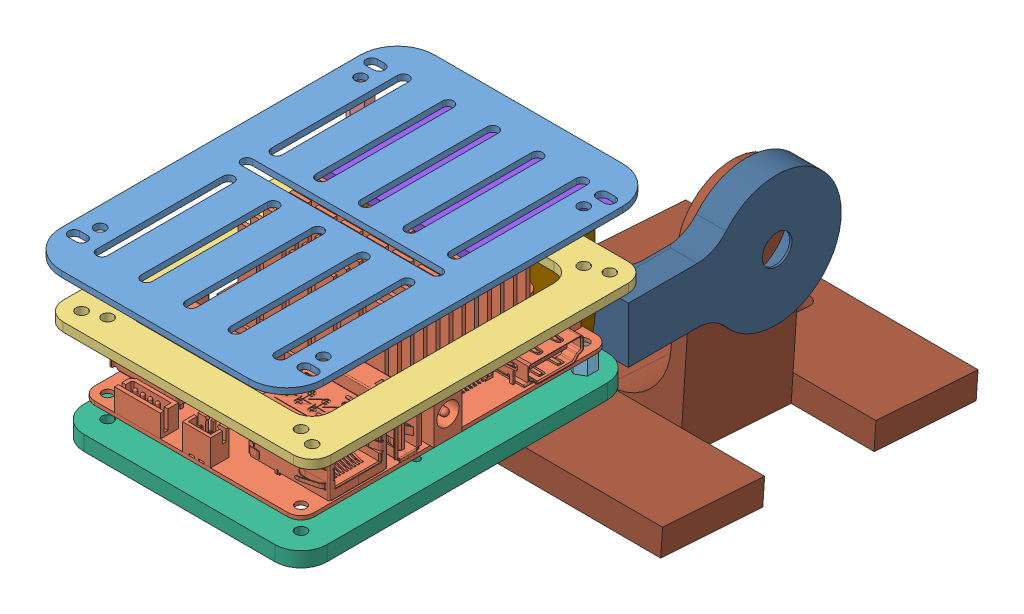
SolidWorks assembly s3820_assam, configuration 預設. Lengths in mm.
Overall size (78.77 89.88 186.6).
12 component instances, 11 part files, 32 mates.
Components (placement in the parent):
- 原底板-1: 原底板 [預設] at origin size (70.5 1.6 100.35)
- Odroid-XU4-1: Odroid-XU4 [Défaut] at (1 -33 0) x (0 0 -1) z (1 0 0) size (84.5 29.98 60.08)
- s380_odroid架-1: s380_odroid架 [預設] at (1 -17.7 0) size (72 2.4 90)
- brown_steel_rod_18-1: brown_steel_rod_18 [預設] at (-25 -33 -38) x (0.819556 0 -0.572999) z (0.572999 0 0.819556) size (5 15.3 5.77)
- brown_steel_rod_18-2: brown_steel_rod_18 [預設] at (-30 -15.3 -35) size (5 15.3 5.77)
- brown_steel_rod_5-1: brown_steel_rod_5 [預設] at (27 -39 -38) size (5 5 5.77)
- 底相機架-1: 底相機架 [Default] at (1 -39 0) x (0 0 1) z (1 0 0) size (89.39 4 65.39)
- c170-1: c170 [Default] at (1 -43 0) x (-1 0 0) z (0 0 1) size (55 4.2 19)
- 雲台架-1: 雲台架 [預設] at (0 -7.4 -20.5) size (54 2.4 38.5)
- 雲台1-1: 雲台1 [Default] at (0 -40.4 -53) x (1 0 0) z (0 -1 0) size (30 37 48)
- 雲台2-1: 雲台2 [Default] at (0 -40.4 -53) x (-0.999996 0.002948 0) z (-0.002948 -0.999996 0) size (39 57.24 35)
- 雲台3-1: 雲台3 [Default] at (15.9558 -55.4128 -91.9867) x (0.002941 0.997712 -0.067551) z (0.000199 0.06755 0.997716) size (60 78.57 85.02)
Mates (geometry in assembly coordinates):
- 同軸心1: concentric aligned: cylinder of s380_odroid架-1 through (32 -15.3 -40) axis (0 -1 0) radius 1.5; cylinder of 原底板-1 through (32 1.6 -40) axis (0 -1 0) radius 1.5
- 同軸心2: concentric aligned: cylinder of s380_odroid架-1 through (-30 -15.3 40) axis (0 -1 0) radius 1.5; cylinder of 原底板-1 through (-30 1.6 40) axis (0 -1 0) radius 1.5
- 同軸心3: concentric anti-aligned: cylinder of Odroid-XU4-1 through (-25 -33 38) axis (0 1 0) radius 1.4224; cylinder of s380_odroid架-1 through (-25 -15.3 38) axis (0 -1 0) radius 1.5
- 同軸心4: concentric anti-aligned: cylinder of Odroid-XU4-1 through (27 -33 -38) axis (0 1 0) radius 1.4224; cylinder of s380_odroid架-1 through (27 -15.3 -38) axis (0 -1 0) radius 1.5
- 同軸心5: concentric anti-aligned: cylinder of Odroid-XU4-1 through (-25 -33 -38) axis (0 1 0) radius 1.4224; cylinder of brown_steel_rod_18-1 through (-25 -17.7 -38) axis (0 -1 0) radius 1.5
- 重合/共線/共點1: coincident anti-aligned: plane of s380_odroid架-1 through (-30 -17.7 -40) normal (0 -1 0); plane of brown_steel_rod_18-1 through (-25 -17.7 -38) normal (0 1 0)
- 重合/共線/共點2: coincident anti-aligned: plane of Odroid-XU4-1 through (27 -33 38) normal (0 1 0); plane of brown_steel_rod_18-1 through (-25 -33 -38) normal (0 -1 0)
- 重合/共線/共點3: coincident anti-aligned: plane of s380_odroid架-1 through (-30 -15.3 -40) normal (0 1 0); plane of brown_steel_rod_18-2 through (-30 -15.3 -35) normal (0 -1 0)
- 同軸心7: concentric aligned: cylinder of 原底板-1 through (-30 1.6 -35) axis (0 -1 0) radius 1.5; cylinder of brown_steel_rod_18-2 through (-30 0 -35) axis (0 -1 0) radius 1.5
- 重合/共線/共點4: coincident anti-aligned: plane of 原底板-1 through (0 0 0) normal (0 -1 0); plane of brown_steel_rod_18-2 through (-30 0 -35) normal (0 1 0)
- 重合/共線/共點6: coincident anti-aligned: plane of Odroid-XU4-1 through (27 -34 38) normal (0 -1 0); plane of brown_steel_rod_5-1 through (27 -34 -38) normal (0 1 0)
- 同軸心16: concentric aligned: cylinder of Odroid-XU4-1 through (-25 -33 38) axis (0 1 0) radius 1.4224; cylinder of 底相機架-1 through (-25 -43 38) axis (0 1 0) radius 1.5
- 同軸心17: concentric anti-aligned: cylinder of brown_steel_rod_5-1 through (27 -34 -38) axis (0 -1 0) radius 1.5; cylinder of 底相機架-1 through (27 -43 -38) axis (0 1 0) radius 1.5
- 同軸心18: concentric anti-aligned: cylinder of Odroid-XU4-1 through (27 -33 -38) axis (0 1 0) radius 1.4224; cylinder of brown_steel_rod_5-1 through (27 -34 -38) axis (0 -1 0) radius 1.5
- 重合/共線/共點7: coincident anti-aligned: plane of brown_steel_rod_5-1 through (27 -39 -38) normal (0 -1 0); plane of 底相機架-1 through (1 -39 0) normal (0 1 0)
- 同軸心19: concentric aligned: cylinder of 底相機架-1 through (25.7 -43 5.7) axis (0 1 0) radius 1; cylinder of c170-1 through (25.7 -44 5.7) axis (0 1 0) radius 1.25
- 同軸心20: concentric aligned: cylinder of 底相機架-1 through (-23.7 -43 -5.7) axis (0 1 0) radius 1; cylinder of c170-1 through (-23.7 -44 -5.7) axis (0 1 0) radius 1.25
- 重合/共線/共點8: coincident anti-aligned: plane of 底相機架-1 through (1 -43 0) normal (0 -1 0); plane of c170-1 through (1 -43 0) normal (0 1 0)
- 相切(T)1: tangent anti-aligned: plane of 原底板-1 through (22.5 1.6 -40.5) normal (1 0 0); cylinder of 雲台架-1 through (24 -5 -20.5) axis (0 -1 0) radius 1.5
- 相切(T)2: tangent anti-aligned: plane of 原底板-1 through (-25.5 1.6 -40.5) normal (1 0 0); cylinder of 雲台架-1 through (-24 -5 -20.5) axis (0 -1 0) radius 1.5
- 平行相距2: distance = 5 mm anti-aligned: plane of 原底板-1 through (0 0 0) normal (0 -1 0); plane of 雲台架-1 through (0 -5 -20.5) normal (0 1 0)
- 同軸心21: concentric aligned: cylinder of 雲台架-1 through (10.5 -5 -20.5) axis (0 -1 0) radius 3; cylinder of 雲台1-1 through (10.5 -7.4 -20.5) axis (0 -1 0) radius 3
- 同軸心22: concentric aligned: cylinder of 雲台架-1 through (-10.5 -5 -49) axis (0 -1 0) radius 3; cylinder of 雲台1-1 through (-10.5 -7.4 -49) axis (0 -1 0) radius 3
- 重合/共線/共點10: coincident anti-aligned: plane of 雲台架-1 through (0 -7.4 -20.5) normal (0 -1 0); plane of 雲台1-1 through (0 -7.4 -53) normal (0 1 0)
- 同軸心23: concentric aligned: cylinder of 雲台1-1 through (0 -40.4 -16) axis (0 0 1) radius 4; cylinder of 雲台2-1 through (0 -40.4 -57) axis (0 0 1) radius 4
- 重合/共線/共點11: coincident anti-aligned: plane of 雲台1-1 through (0 -40.4 -53) normal (0 0 -1); plane of 雲台2-1 through (0 -40.4 -53) normal (0 0 1)
- 同軸心24: concentric aligned: cylinder of 原底板-1 through (24 1.6 -40.5) axis (0 -1 0) radius 1.5; cylinder of 雲台架-1 through (24 -5 -40.5) axis (0 -1 0) radius 1.5
- 重合/共線/共點12: coincident anti-aligned: plane of 雲台2-1 through (15.9999 -40.4472 -53) normal (-0.999996 0.002948 0); plane of 雲台3-1 through (15.9558 -55.4128 -91.9867) normal (0.999996 -0.002948 0)
- 同軸心25: concentric anti-aligned: cylinder of 雲台2-1 through (23.9999 -40.4707 -93) axis (-0.999996 0.002948 0) radius 4; cylinder of 雲台3-1 through (11.9999 -40.4354 -93) axis (0.999996 -0.002948 0) radius 4
- 重合/共線/共點13: coincident aligned: plane of 原底板-1 through (0 0 0) normal (0 1 0); plane of assembly through (0 0 0) normal (0 1 0)
- 重合/共線/共點14: coincident aligned: plane of 原底板-1 through (0 0 0) normal (1 0 0); plane of assembly through (0 0 0) normal (1 0 0)
- 重合/共線/共點15: coincident aligned: plane of 原底板-1 through (0 0 0) normal (0 0 1); plane of assembly through (0 0 0) normal (0 0 1)
